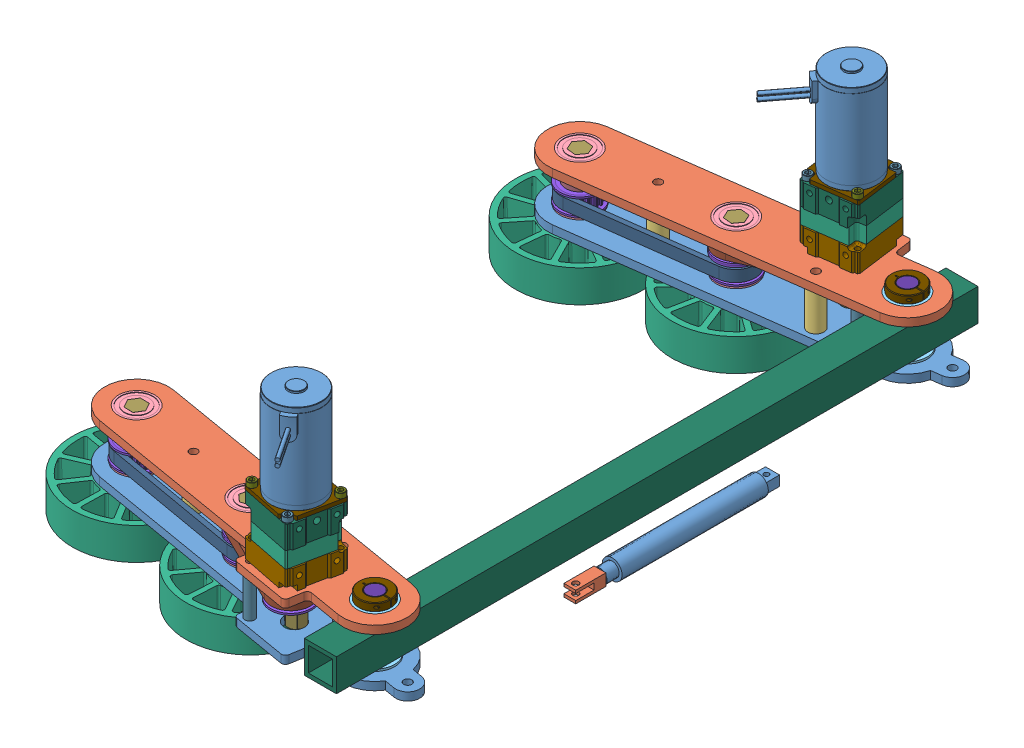
SolidWorks assembly IntakeV7Assem, configuration Default. Lengths in mm.
Overall size (329.15 194.94 529.24).
125 component instances, 38 part files, 146 mates.
Components (placement in the parent):
- IntakeV7PlateBottom-1: IntakeV7PlateBottom [Default] at (175.2787 -57.2575 -302.756) x (0.167502 0 -0.985872) z (0.985872 0 0.167502) size (67.49 6.35 297.21)
- IntakeV7PlateBottom-2: IntakeV7PlateBottom [Default] at (169.8416 -50.9075 -403.3696) x (0.134021 0 0.990979) z (0.990979 0 -0.134021) size (67.49 6.35 297.21)
- IntakeV7PlateTop-1: IntakeV7PlateTop [Default] at (175.2787 -18.6495 -302.756) x (0.167502 0 -0.985872) z (0.985872 0 0.167502) size (67.49 6.35 281.33)
- IntakeV7PlateTop-2: IntakeV7PlateTop [Default] at (169.8416 -12.2995 -403.3696) x (0.134021 0 0.990979) z (0.990979 0 -0.134021) size (67.49 6.35 281.33)
- PlateSpacer-1: PlateSpacer [Default] at (-346.0992 -18.6495 -177.4979) x (-0.995575 0 0.093974) z (0 -1 0) size (12.7 12.7 32.26)
- PlateSpacer-2: PlateSpacer [Default] at (-222.5722 -18.6495 -171.9688) x (1 0 0) z (0 -1 0) size (12.7 12.7 32.26)
- PlateSpacer-3: PlateSpacer [Default] at (-223.3522 -50.9075 -547.5543) x (1 0 0) z (0 1 0) size (12.7 12.7 32.26)
- PlateSpacer-4: PlateSpacer [Default] at (-346.9956 -50.9075 -546.2114) x (1 0 0) z (0 1 0) size (12.7 12.7 32.26)
- HalfHexBearing-1: HalfHexBearing [Default] at (-400.3258 -12.2995 -186.7111) x (0.520029 0 -0.854148) z (-0.854148 0 -0.520029) size (31.12 7.94 31.12)
- HalfHexBearing-2: HalfHexBearing [Default] at (-400.3258 -57.2575 -186.7111) x (-0.520029 0 0.854148) z (-0.854148 0 -0.520029) size (31.12 7.94 31.12)
- HalfHexBearing-3: HalfHexBearing [Default] at (-291.8726 -12.2995 -168.2847) x (-0.20332 0 0.979112) z (0.979112 0 0.20332) size (31.12 7.94 31.12)
- HalfHexBearing-4: HalfHexBearing [Default] at (-291.8726 -57.2575 -168.2847) x (0.20332 0 -0.979112) z (0.979112 0 0.20332) size (31.12 7.94 31.12)
- HalfHexBearing-5: HalfHexBearing [Default] at (-401.5031 -12.2995 -538.8398) x (-0.408462 0 -0.912775) z (-0.912775 0 0.408462) size (31.12 7.94 31.12)
- HalfHexBearing-6: HalfHexBearing [Default] at (-401.5031 -57.2575 -538.8398) x (0.408462 0 0.912775) z (-0.912775 0 0.408462) size (31.12 7.94 31.12)
- HalfHexBearing-7: HalfHexBearing [Default] at (-292.4881 -12.2995 -553.5831) x (-0.408462 0 -0.912775) z (-0.912775 0 0.408462) size (31.12 7.94 31.12)
- HalfHexBearing-8: HalfHexBearing [Default] at (-292.4881 -57.2575 -553.5831) x (0.408462 0 0.912775) z (-0.912775 0 0.408462) size (31.12 7.94 31.12)
- HalfRoundBearing-1: HalfRoundBearing [Default] at (-173.0483 -12.2995 -148.0962) x (0.837169 0 0.546944) z (0.546944 0 -0.837169) size (31.12 7.94 31.12)
- HalfRoundBearing-2: HalfRoundBearing [Default] at (-173.0483 -57.2575 -148.0962) x (-0.997571 0 -0.069658) z (0.069658 0 -0.997571) size (31.12 7.94 31.12)
- HalfRoundBearing-3: HalfRoundBearing [Default] at (-173.0483 -57.2575 -569.7362) x (-1 0 0) z (0 0 -1) size (31.12 7.94 31.12)
- HalfRoundBearing-4: HalfRoundBearing [Default] at (-173.0483 -12.2995 -569.7362) x (0.837169 0 0.546944) z (0.546944 0 -0.837169) size (31.12 7.94 31.12)
- 4inCompliantWheel-1: 4inCompliantWheel [Default] at (-284.8008 -77.497 -183.4) x (0.20332 0 -0.979112) z (0 1 0) size (101.6 101.6 25.74)
  - 4IN Compliant Wheel FINAL Overmold-1: 4IN Compliant Wheel FINAL Overmold [Default] at (-16.2374 3.8509 18.652) size (101.6 101.6 25.74)
  - 2in Wheel Intergrated 0500 HEX Hub-1: 2in Wheel Intergrated 0500 HEX Hub [Default] at (-16.2374 3.8509 5.952) x (-1 0 0) z (0 0 -1) size (41.91 41.91 25.4)
- 4inCompliantWheel-2: 4inCompliantWheel [Default] at (-416.4692 -77.497 -190.939) x (-0.999729 0 -0.023285) z (0 1 0) size (101.6 101.6 25.74)
  - 4IN Compliant Wheel FINAL Overmold-1: 4IN Compliant Wheel FINAL Overmold [Default] at (-16.2374 3.8509 18.652) size (101.6 101.6 25.74)
  - 2in Wheel Intergrated 0500 HEX Hub-1: 2in Wheel Intergrated 0500 HEX Hub [Default] at (-16.2374 3.8509 5.952) x (-1 0 0) z (0 0 -1) size (41.91 41.91 25.4)
- 4inCompliantWheel-3: 4inCompliantWheel [Default] at (-417.2595 -77.497 -544.3371) x (-0.994718 0 -0.102649) z (0 1 0) size (101.6 101.6 25.74)
  - 4IN Compliant Wheel FINAL Overmold-1: 4IN Compliant Wheel FINAL Overmold [Default] at (-16.2374 3.8509 18.652) size (101.6 101.6 25.74)
  - 2in Wheel Intergrated 0500 HEX Hub-1: 2in Wheel Intergrated 0500 HEX Hub [Default] at (-16.2374 3.8509 5.952) x (-1 0 0) z (0 0 -1) size (41.91 41.91 25.4)
- 4inCompliantWheel-4: 4inCompliantWheel [Default] at (-305.1271 -77.497 -542.6863) x (-0.586256 0 0.810126) z (0 1 0) size (101.6 101.6 25.74)
  - 4IN Compliant Wheel FINAL Overmold-1: 4IN Compliant Wheel FINAL Overmold [Default] at (-16.2374 3.8509 18.652) size (101.6 101.6 25.74)
  - 2in Wheel Intergrated 0500 HEX Hub-1: 2in Wheel Intergrated 0500 HEX Hub [Default] at (-16.2374 3.8509 5.952) x (-1 0 0) z (0 0 -1) size (41.91 41.91 25.4)
- 18THTD9MMPulley-1: 18THTD9MMPulley [Default] at (-229.0207 -27.57 -137.4686) x (0.947792 0 -0.31889) z (0 -1 0) size (32 32 14.5)
- 18THTD9MMPulley-2: 18THTD9MMPulley [Default] at (-227.7775 -27.57 -580.2764) x (1 0 0) z (0 1 0) size (32 32 14.5)
- 18THTD9MMPulley-3: 18THTD9MMPulley [Default] at (-291.8726 -42.07 -168.2847) x (0.746276 0 0.665636) z (0 -1 0) size (32 32 14.5)
- 18THTD9MMPulley-4: 18THTD9MMPulley [Default] at (-400.3258 -42.07 -186.7111) x (-0.520029 0 0.854148) z (0 1 0) size (32 32 14.5)
- 18THTD9MMPulley-5: 18THTD9MMPulley [Default] at (-401.5031 -42.07 -538.8398) x (1 0 0) z (0 1 0) size (32 32 14.5)
- 18THTD9MMPulley-6: 18THTD9MMPulley [Default] at (-292.4881 -42.07 -553.5831) x (1 0 0) z (0 1 0) size (32 32 14.5)
- 18THTD9MMPulley-7: 18THTD9MMPulley [Default] at (-291.8726 -27.57 -168.2847) x (0.20332 0 -0.979112) z (0 1 0) size (32 32 14.5)
- 18THTD9MMPulley-8: 18THTD9MMPulley [Default] at (-292.4881 -27.57 -553.5831) x (1 0 0) z (0 1 0) size (32 32 14.5)
- VersaPlanetary_v2_Single_Stage_10_1_with_BAG-1: VersaPlanetary_v2_Single_Stage_10_1_with_BAG [Default] at (-206.5577 4.3255 -136.7173) x (0 -1 0) z (0.197729 0 -0.980257) size (163.4 63.56 63.56)
  - 217-2625-026 Rev1-1: 217-2625-026 Rev1 [Default] at (-6.5 22.225 0) x (0 -1 0) z (-1 0 0) size (44.45 42 18.13)
  - 217-2742-001 Rev4-1: 217-2742-001 Rev4 [Default] at (0.2002 22.225 0) x (1 0 0) z (0 -0.092627 0.995701) size (7 28 28)
  - 217-2742-001 Rev4-2: 217-2742-001 Rev4 [Default] at (8.2002 22.225 0) size (7 28 28)
  - 217-2625-017 Rev1_9714K61-1: 217-2625-017 Rev1_9714K61 [Default] at (7.42 22.3002 -0.342) x (0 0.56703 0.823697) z (0 -0.823697 0.56703) size (28.51 4.98 30.18)
  - 217-2625-003 Rev1-1: 217-2625-003 Rev1 [Default] at (7.4478 22.225 0) x (0 -1 0) z (1 0 0) size (17 17 64.12)
  - 217-2625-018 Rev1_98541A410-1: 217-2625-018 Rev1_98541A410 [Default] at (-0.7046 22.225 0) x (1 0 0) z (0 -0.017452 0.999848) size (1 19.6 17.4)
  - 832-1750-Ring-Gear-Screw_SSA0832-0500ZC-1: 832-1750-Ring-Gear-Screw_SSA0832-0500ZC [Default] at (-30.7 4.725 -17.5) x (0 0.997447 0.071411) z (0 -0.071411 0.997447) size (6.73 48.51 6.73)
  - 832-1750-Ring-Gear-Screw_SSA0832-0500ZC-2: 832-1750-Ring-Gear-Screw_SSA0832-0500ZC [Default] at (-30.7 39.725 17.5) x (0 0.005929 0.999982) z (0 -0.999982 0.005929) size (6.73 48.51 6.73)
  - 217-2625-025 Rev1-1: 217-2625-025 Rev1 [Default] at (-23.2 22.225 0) x (0 -1 0) z (-1 0 0) size (44.45 42 18)
  - 217-4649-002 Rev1_SSA0832-0500ZC-1: 217-4649-002 Rev1_SSA0832-0500ZC [Default] at (-33.7 4.2645 17.9605) x (0 0.33842 -0.940995) z (0 0.940995 0.33842) size (6.73 16.76 6.73)
  - 217-4649-002 Rev1_SSA0832-0500ZC-2: 217-4649-002 Rev1_SSA0832-0500ZC [Default] at (-33.7 40.1855 -17.9605) x (0 -0.308932 -0.951084) z (0 0.951084 -0.308932) size (6.73 16.76 6.73)
  - 217-4649-006 Rev1_SSA0004-008BA-1: 217-4649-006 Rev1_SSA0004-008BA [Default] at (-30.7 22.225 12.5) x (0 0.5 -0.866025) z (0 -0.866025 -0.5) size (7 14 7)
  - 217-4649-006 Rev1_SSA0004-008BA-2: 217-4649-006 Rev1_SSA0004-008BA [Default] at (-30.7 22.225 -12.5) x (0 -0.5 0.866025) z (0 0.866025 0.5) size (7 14 7)
  - 217-2822-003 Rev4-1: 217-2822-003 Rev4 [Default] at (-32.2 22.225 0) x (0 -1 0) z (-1 0 0) size (42 42 4.8)
  - 217-3351 Rev2-1: 217-3351 Rev2 [Default] at (-33.7 22.225 0) x (0 0 1) z (1 0 0) size (59.11 59.11 84.5)
  - 217-2820 Rev1_Public-1: 217-2820 Rev1_Public [Default] at (-4.6546 22.225 0) x (0 -0.456494 0.889726) z (-1 0 0) size (39.26 38.9 17.4)
    - 217-2625-100-1: 217-2625-100 [Default] at origin size (39.26 38.9 12.7)
      - 217-2625-008 Rev1-1: 217-2625-008 Rev1 [Default] at origin size (34.7 34.7 4.7)
      - 217-2625-010 Rev1-1: 217-2625-010 Rev1 [Default] at (0 10.193 3.65) x (0.999813 0.019336 0) z (0 0 1) size (4 4 12)
      - 217-2625-010 Rev1-2: 217-2625-010 Rev1 [Default] at (8.691 -5.3258 3.65) size (4 4 12)
      - 217-2625-010 Rev1-3: 217-2625-010 Rev1 [Default] at (-8.691 -5.3258 3.65) size (4 4 12)
      - 217-2625-005 Rev1_Planet_Revolving_Follower01-1: 217-2625-005 Rev1_Planet_Revolving_Follower01 [Default] at (8.691 -5.3258 6.35) x (0.932816 0.360354 0) z (0 0 1) size (16.91 16.92 8)
      - 217-2625-005 Rev1_Planet_Revolving_Follower01-2: 217-2625-005 Rev1_Planet_Revolving_Follower01 [Default] at (-8.691 -5.3258 6.35) x (-0.932788 -0.360426 0) z (0 0 1) size (16.91 16.92 8)
      - 217-2625-005 Rev1_Planet_Revolving_Follower01-3: 217-2625-005 Rev1_Planet_Revolving_Follower01 [Default] at (0 10.193 6.35) x (0.893583 0.448898 0) z (0 0 1) size (16.91 16.92 8)
    - 217-2625-007 Rev1_Public-1: 217-2625-007 Rev1_Public [Default] at (0 0 6.7) x (0.992772 0.120019 0) z (0 0 1) size (14.49 14.49 12.72)
  - 217-2816-001 Rev1-1: 217-2816-001 Rev1 [Default] at (-6.35 22.225 0) x (0 -1 0) z (1 0 0) size (42 42 14.5)
  - 217-4649-001 Rev1-1: 217-4649-001 Rev1 [Default] at (-20.046 22.225 0) x (0 -1 0) z (1 0 0) size (18 18 13)
  - 217-4649-007 Rev1_94105A824-1: 217-4649-007 Rev1_94105A824 [Default] at (-25.521 22.225 -6.7835) x (-0.996104 -0.088191 0) z (0 0 -1) size (4.83 4.83 4.9)
  - 217-2625-011 Rev1-1: 217-2625-011 Rev1 [Default] at (-24.7818 22.225 0) x (0 0 1) z (0 -1 0) size (8.01 7.5 7.94)
- VersaPlanetary_v2_Single_Stage_10_1_with_BAG-2: VersaPlanetary_v2_Single_Stage_10_1_with_BAG [Default] at (-224.7989 4.3255 -558.2519) x (0 -1 0) z (0.990979 0 -0.134021) size (163.4 63.56 63.56)
  - 217-2625-026 Rev1-1: 217-2625-026 Rev1 [Default] at (-6.5 22.225 0) x (0 -1 0) z (-1 0 0) size (44.45 42 18.13)
  - 217-2742-001 Rev4-1: 217-2742-001 Rev4 [Default] at (0.2002 22.225 0) x (1 0 0) z (0 -0.092627 0.995701) size (7 28 28)
  - 217-2742-001 Rev4-2: 217-2742-001 Rev4 [Default] at (8.2002 22.225 0) size (7 28 28)
  - 217-2625-017 Rev1_9714K61-1: 217-2625-017 Rev1_9714K61 [Default] at (7.42 22.3002 -0.342) x (0 0.56703 0.823697) z (0 -0.823697 0.56703) size (28.51 4.98 30.18)
  - 217-2625-003 Rev1-1: 217-2625-003 Rev1 [Default] at (7.4478 22.225 0) x (0 -1 0) z (1 0 0) size (17 17 64.12)
  - 217-2625-018 Rev1_98541A410-1: 217-2625-018 Rev1_98541A410 [Default] at (-0.7046 22.225 0) x (1 0 0) z (0 -0.017452 0.999848) size (1 19.6 17.4)
  - 832-1750-Ring-Gear-Screw_SSA0832-0500ZC-1: 832-1750-Ring-Gear-Screw_SSA0832-0500ZC [Default] at (-30.7 4.725 -17.5) x (0 0.997447 0.071411) z (0 -0.071411 0.997447) size (6.73 48.51 6.73)
  - 832-1750-Ring-Gear-Screw_SSA0832-0500ZC-2: 832-1750-Ring-Gear-Screw_SSA0832-0500ZC [Default] at (-30.7 39.725 17.5) x (0 0.005929 0.999982) z (0 -0.999982 0.005929) size (6.73 48.51 6.73)
  - 217-2625-025 Rev1-1: 217-2625-025 Rev1 [Default] at (-23.2 22.225 0) x (0 -1 0) z (-1 0 0) size (44.45 42 18)
  - 217-4649-002 Rev1_SSA0832-0500ZC-1: 217-4649-002 Rev1_SSA0832-0500ZC [Default] at (-33.7 4.2645 17.9605) x (0 0.33842 -0.940995) z (0 0.940995 0.33842) size (6.73 16.76 6.73)
  - 217-4649-002 Rev1_SSA0832-0500ZC-2: 217-4649-002 Rev1_SSA0832-0500ZC [Default] at (-33.7 40.1855 -17.9605) x (0 -0.308932 -0.951084) z (0 0.951084 -0.308932) size (6.73 16.76 6.73)
  - 217-4649-006 Rev1_SSA0004-008BA-1: 217-4649-006 Rev1_SSA0004-008BA [Default] at (-30.7 22.225 12.5) x (0 0.5 -0.866025) z (0 -0.866025 -0.5) size (7 14 7)
  - 217-4649-006 Rev1_SSA0004-008BA-2: 217-4649-006 Rev1_SSA0004-008BA [Default] at (-30.7 22.225 -12.5) x (0 -0.5 0.866025) z (0 0.866025 0.5) size (7 14 7)
  - 217-2822-003 Rev4-1: 217-2822-003 Rev4 [Default] at (-32.2 22.225 0) x (0 -1 0) z (-1 0 0) size (42 42 4.8)
  - 217-3351 Rev2-1: 217-3351 Rev2 [Default] at (-33.7 22.225 0) x (0 0 1) z (1 0 0) size (59.11 59.11 84.5)
  - 217-2820 Rev1_Public-1: 217-2820 Rev1_Public [Default] at (-4.6546 22.225 0) x (0 -0.456494 0.889726) z (-1 0 0) size (39.26 38.9 17.4)
    - 217-2625-100-1: 217-2625-100 [Default] at origin size (39.26 38.9 12.7)
      - 217-2625-008 Rev1-1: 217-2625-008 Rev1 [Default] at origin size (34.7 34.7 4.7)
      - 217-2625-010 Rev1-1: 217-2625-010 Rev1 [Default] at (0 10.193 3.65) x (0.999813 0.019336 0) z (0 0 1) size (4 4 12)
      - 217-2625-010 Rev1-2: 217-2625-010 Rev1 [Default] at (8.691 -5.3258 3.65) size (4 4 12)
      - 217-2625-010 Rev1-3: 217-2625-010 Rev1 [Default] at (-8.691 -5.3258 3.65) size (4 4 12)
      - 217-2625-005 Rev1_Planet_Revolving_Follower01-1: 217-2625-005 Rev1_Planet_Revolving_Follower01 [Default] at (8.691 -5.3258 6.35) x (0.932816 0.360354 0) z (0 0 1) size (16.91 16.92 8)
      - 217-2625-005 Rev1_Planet_Revolving_Follower01-2: 217-2625-005 Rev1_Planet_Revolving_Follower01 [Default] at (-8.691 -5.3258 6.35) x (-0.932788 -0.360426 0) z (0 0 1) size (16.91 16.92 8)
      - 217-2625-005 Rev1_Planet_Revolving_Follower01-3: 217-2625-005 Rev1_Planet_Revolving_Follower01 [Default] at (0 10.193 6.35) x (0.893583 0.448898 0) z (0 0 1) size (16.91 16.92 8)
    - 217-2625-007 Rev1_Public-1: 217-2625-007 Rev1_Public [Default] at (0 0 6.7) x (0.992772 0.120019 0) z (0 0 1) size (14.49 14.49 12.72)
  - 217-2816-001 Rev1-1: 217-2816-001 Rev1 [Default] at (-6.35 22.225 0) x (0 -1 0) z (1 0 0) size (42 42 14.5)
  - 217-4649-001 Rev1-1: 217-4649-001 Rev1 [Default] at (-20.046 22.225 0) x (0 -1 0) z (1 0 0) size (18 18 13)
  - 217-4649-007 Rev1_94105A824-1: 217-4649-007 Rev1_94105A824 [Default] at (-25.521 22.225 -6.7835) x (-0.996104 -0.088191 0) z (0 0 -1) size (4.83 4.83 4.9)
  - 217-2625-011 Rev1-1: 217-2625-011 Rev1 [Default] at (-24.7818 22.225 0) x (0 0 1) z (0 -1 0) size (8.01 7.5 7.94)
- BetweenWheelsBelt-1: BetweenWheelsBelt [Default] at (-400.3258 -42.07 -186.7111) x (0.985049 0 0.172276) z (0 -1 0) size (140.93 30.93 9)
- BetweenWheelsBelt-2: BetweenWheelsBelt [Default] at (-401.5031 -42.07 -538.8398) x (0.991616 0 -0.129217) z (0 1 0) size (140.93 30.93 9)
- WheelToGearboxBelt-1: WheelToGearboxBelt [Default] at (-229.0207 -27.57 -137.4686) x (-0.897885 0 -0.44023) z (0 1 0) size (100.93 30.93 9)
- WheelToGearboxBelt-2: WheelToGearboxBelt [Default] at (-292.4253 -27.57 -553.0537) x (0.918758 0 -0.394822) z (0 -1 0) size (100.93 30.93 9)
- WheelAxle-1: WheelAxle [Default] at (-401.4916 -84.2577 -538.8386) x (-0.586256 0 0.810126) z (-0.810126 0 -0.586256) size (14.66 71.96 12.7)
- WheelAxle-2: WheelAxle [Default] at (-292.5043 -84.2577 -553.5948) x (0.586256 0 -0.810126) z (0.810126 0 0.586256) size (14.66 71.96 12.7)
- WheelAxle-3: WheelAxle [Default] at (-291.8531 -84.2577 -168.2806) x (0.20332 0 -0.979112) z (0.979112 0 0.20332) size (14.66 71.96 12.7)
- WheelAxle-4: WheelAxle [Default] at (-400.3429 -84.2577 -186.7215) x (0.520029 0 -0.854148) z (0.854148 0 0.520029) size (14.66 71.96 12.7)
- FrontAxleSpacer-2: FrontAxleSpacer [Default] at (-400.3258 -34.8166 -186.7111) size (22.23 14.58 22.23)
- GearboxMountSpacers-1: GearboxMountSpacers [Default] at (-207.3879 -50.9075 -154.1137) size (7.62 32.26 7.62)
- GearboxMountSpacers-2: GearboxMountSpacers [Default] at (-248.8182 -50.9075 -124.717) size (7.62 32.26 7.62)
- GearboxMountSpacers-3: GearboxMountSpacers [Default] at (-207.572 -50.9075 -564.885) size (7.62 32.26 7.62)
- GearboxMountSpacers-4: GearboxMountSpacers [Default] at (-247.9831 -50.9075 -595.6678) size (7.62 32.26 7.62)
- ArmMountBar-1: ArmMountBar [Default] at (-173.0483 -36.62 -612.9162) size (50.8 25.4 508)
- PivotSpacer-1: PivotSpacer [Default] at (-173.0483 -20.237 -148.0962) x (1 0 0) z (0 -1 0) size (19.05 19.05 3.68)
- PivotSpacer-2: PivotSpacer [Default] at (-173.0483 -20.237 -569.7362) x (1 0 0) z (0 -1 0) size (19.05 19.05 3.68)
- FrontAxleSpacer-1: FrontAxleSpacer [Default] at (-401.5031 -34.8166 -538.8398) size (22.23 14.58 22.23)
- ArmPivotAxle-1: ArmPivotAxle [Default] at (-173.0483 -63.6075 -148.0962) size (12.7 57.66 12.7)
- ArmPivotAxle-2: ArmPivotAxle [Default] at (-173.0483 -63.6075 -569.7362) size (12.7 57.66 12.7)
- HalfRoundShaftCollar-1: HalfRoundShaftCollar [Default] at (-168.5329 -8.5224 -150.7118) x (1 0 0) z (0 -1 0) size (25.39 25.4 6.35)
- HalfRoundShaftCollar-2: HalfRoundShaftCollar [Default] at (-169.5026 -59.8304 -151.9248) x (0.955715 0 -0.294293) z (0 -1 0) size (25.39 25.4 6.35)
- HalfRoundShaftCollar-3: HalfRoundShaftCollar [Default] at (-168.5329 -8.5224 -572.3518) x (1 0 0) z (0 -1 0) size (25.39 25.4 6.35)
- HalfRoundShaftCollar-4: HalfRoundShaftCollar [Default] at (-169.3234 -59.8304 -573.3906) x (0.968711 0 -0.248193) z (0 -1 0) size (25.39 25.4 6.35)
- CylinderBody-1: CylinderBody [Default] at (-149.2993 -61.9565 -428.0042) x (0 -1 0) z (0 0 1) size (15.75 15.75 136.65)
- PistonRod-1: PistonRod [Default] at (-149.2993 -61.9565 -302.5282) size (9.4 9.4 125.48)
Mates (geometry in assembly coordinates):
- Concentric1: concentric aligned: cylinder of IntakeV7PlateBottom-1 through (-400.3258 -50.9075 -186.7111) axis (0 -1 0) radius 14.2748; cylinder of IntakeV7PlateTop-1 through (-400.3258 -12.2995 -186.7111) axis (0 -1 0) radius 14.2748
- Concentric2: concentric aligned: cylinder of IntakeV7PlateBottom-1 through (-173.0483 -50.9075 -148.0962) axis (0 -1 0) radius 14.2748; cylinder of IntakeV7PlateTop-1 through (-173.0483 -12.2995 -148.0962) axis (0 -1 0) radius 14.2748
- Distance1: distance = 32.258 mm anti-aligned: plane of IntakeV7PlateTop-1 through (175.2787 -18.6495 -302.756) normal (0 -1 0); plane of IntakeV7PlateBottom-1 through (175.2787 -50.9075 -302.756) normal (0 1 0)
- Coincident2: coincident aligned: plane of IntakeV7PlateBottom-1 through (175.2787 -57.2575 -302.756) normal (0 -1 0); plane of IntakeV7PlateBottom-2 through (169.8416 -57.2575 -403.3696) normal (0 -1 0)
- Concentric3: concentric aligned: cylinder of IntakeV7PlateBottom-2 through (-173.0483 -57.2575 -569.7362) axis (0 1 0) radius 14.2748; cylinder of IntakeV7PlateTop-2 through (-173.0483 -18.6495 -569.7362) axis (0 1 0) radius 14.2748
- Concentric4: concentric aligned: cylinder of IntakeV7PlateBottom-2 through (-401.5031 -57.2575 -538.8398) axis (0 1 0) radius 14.2748; cylinder of IntakeV7PlateTop-2 through (-401.5031 -18.6495 -538.8398) axis (0 1 0) radius 14.2748
- Coincident3: coincident aligned: plane of IntakeV7PlateTop-1 through (175.2787 -12.2995 -302.756) normal (0 1 0); plane of IntakeV7PlateTop-2 through (169.8416 -12.2995 -403.3696) normal (0 1 0)
- Coincident4: coincident anti-aligned: plane of IntakeV7PlateTop-1 through (175.2787 -18.6495 -302.756) normal (0 -1 0); plane of PlateSpacer-1 through (-346.0992 -18.6495 -177.4979) normal (0 1 0)
- Coincident5: coincident anti-aligned: plane of IntakeV7PlateTop-1 through (175.2787 -18.6495 -302.756) normal (0 -1 0); plane of PlateSpacer-2 through (-222.5722 -18.6495 -171.9688) normal (0 1 0)
- Coincident6: coincident anti-aligned: plane of IntakeV7PlateTop-2 through (169.8416 -18.6495 -403.3696) normal (0 -1 0); plane of PlateSpacer-4 through (-346.9956 -18.6495 -546.2114) normal (0 1 0)
- Coincident7: coincident anti-aligned: plane of IntakeV7PlateBottom-2 through (169.8416 -50.9075 -403.3696) normal (0 1 0); plane of PlateSpacer-3 through (-223.3522 -50.9075 -547.5543) normal (0 -1 0)
- Concentric9: concentric anti-aligned: cylinder of IntakeV7PlateTop-2 through (-401.5031 -18.6495 -538.8398) axis (0 1 0) radius 14.2748; cylinder of HalfHexBearing-5 through (-401.5031 -12.2995 -538.8398) axis (0 -1 0) radius 14.2748
- Coincident8: coincident anti-aligned: plane of IntakeV7PlateTop-2 through (169.8416 -18.6495 -403.3696) normal (0 -1 0); plane of HalfHexBearing-5 through (-407.8578 -18.6495 -553.0403) normal (0 1 0)
- Concentric10: concentric aligned: cylinder of IntakeV7PlateBottom-2 through (-401.5031 -57.2575 -538.8398) axis (0 1 0) radius 14.2748; cylinder of HalfHexBearing-6 through (-401.5031 -57.2575 -538.8398) axis (0 1 0) radius 14.2748
- Coincident9: coincident anti-aligned: plane of IntakeV7PlateBottom-2 through (169.8416 -50.9075 -403.3696) normal (0 1 0); plane of HalfHexBearing-6 through (-395.1485 -50.9075 -524.6393) normal (0 -1 0)
- Concentric11: concentric aligned: cylinder of IntakeV7PlateTop-1 through (-400.3258 -12.2995 -186.7111) axis (0 -1 0) radius 14.2748; cylinder of HalfHexBearing-1 through (-400.3258 -12.2995 -186.7111) axis (0 -1 0) radius 14.2748
- Concentric12: concentric anti-aligned: cylinder of IntakeV7PlateBottom-1 through (-400.3258 -50.9075 -186.7111) axis (0 -1 0) radius 14.2748; cylinder of HalfHexBearing-2 through (-400.3258 -57.2575 -186.7111) axis (0 1 0) radius 14.2748
- Coincident11: coincident anti-aligned: plane of IntakeV7PlateBottom-1 through (175.2787 -50.9075 -302.756) normal (0 1 0); plane of HalfHexBearing-2 through (-408.4162 -50.9075 -173.4227) normal (0 -1 0)
- Concentric13: concentric aligned: cylinder of IntakeV7PlateTop-1 through (-291.8726 -12.2995 -168.2847) axis (0 -1 0) radius 14.2748; cylinder of HalfHexBearing-3 through (-291.8726 -12.2995 -168.2847) axis (0 -1 0) radius 14.2748
- Coincident12: coincident anti-aligned: plane of IntakeV7PlateTop-1 through (175.2787 -18.6495 -302.756) normal (0 -1 0); plane of HalfHexBearing-3 through (-295.0358 -18.6495 -153.0521) normal (0 1 0)
- Concentric14: concentric anti-aligned: cylinder of IntakeV7PlateBottom-1 through (-291.8726 -50.9075 -168.2847) axis (0 -1 0) radius 14.2748; cylinder of HalfHexBearing-4 through (-291.8726 -57.2575 -168.2847) axis (0 1 0) radius 14.2748
- Coincident13: coincident anti-aligned: plane of IntakeV7PlateBottom-1 through (175.2787 -50.9075 -302.756) normal (0 1 0); plane of HalfHexBearing-4 through (-288.7095 -50.9075 -183.5172) normal (0 -1 0)
- Concentric15: concentric anti-aligned: cylinder of IntakeV7PlateTop-2 through (-292.4881 -18.6495 -553.5831) axis (0 1 0) radius 14.2748; cylinder of HalfHexBearing-7 through (-292.4881 -12.2995 -553.5831) axis (0 -1 0) radius 14.2748
- Coincident14: coincident anti-aligned: plane of IntakeV7PlateTop-2 through (169.8416 -18.6495 -403.3696) normal (0 -1 0); plane of HalfHexBearing-7 through (-298.8428 -18.6495 -567.7836) normal (0 1 0)
- Concentric16: concentric aligned: cylinder of IntakeV7PlateBottom-2 through (-292.4881 -57.2575 -553.5831) axis (0 1 0) radius 14.2748; cylinder of HalfHexBearing-8 through (-292.4881 -57.2575 -553.5831) axis (0 1 0) radius 14.2748
- Coincident15: coincident anti-aligned: plane of IntakeV7PlateBottom-2 through (169.8416 -50.9075 -403.3696) normal (0 1 0); plane of HalfHexBearing-8 through (-286.1335 -50.9075 -539.3826) normal (0 -1 0)
- Coincident16: coincident aligned: plane of HalfHexBearing-7 through (-295.4878 -12.2995 -560.2864) normal (-0.102649 0 0.994718); plane of HalfHexBearing-8 through (-288.1827 -57.2575 -559.5326) normal (-0.102649 0 0.994718)
- Coincident17: coincident aligned: plane of HalfHexBearing-5 through (-404.5028 -12.2995 -545.5431) normal (-0.102649 0 0.994718); plane of HalfHexBearing-6 through (-397.1977 -57.2575 -544.7893) normal (-0.102649 0 0.994718)
- Coincident18: coincident aligned: plane of HalfHexBearing-1 through (-396.5068 -12.2995 -192.9839) normal (-0.877433 0 0.479699); plane of HalfHexBearing-2 through (-392.9839 -57.2575 -186.5401) normal (-0.877433 0 0.479699)
- Coincident19: coincident aligned: plane of HalfHexBearing-3 through (-293.3658 -12.2995 -161.0942) normal (0.665636 0 -0.746276); plane of HalfHexBearing-4 through (-298.8464 -57.2575 -165.9825) normal (0.665636 0 -0.746276)
- Concentric17: concentric aligned: cylinder of IntakeV7PlateTop-1 through (-173.0483 -12.2995 -148.0962) axis (0 -1 0) radius 14.2748; cylinder of HalfRoundBearing-1 through (-173.0483 -12.2995 -148.0962) axis (0 -1 0) radius 14.2875
- Coincident20: coincident anti-aligned: plane of IntakeV7PlateTop-1 through (175.2787 -18.6495 -302.756) normal (0 -1 0); plane of HalfRoundBearing-1 through (-160.024 -18.6495 -139.5871) normal (0 1 0)
- Concentric18: concentric anti-aligned: cylinder of IntakeV7PlateBottom-1 through (-173.0483 -50.9075 -148.0962) axis (0 -1 0) radius 14.2748; cylinder of HalfRoundBearing-2 through (-173.0483 -57.2575 -148.0962) axis (0 1 0) radius 14.2875
- Concentric19: concentric anti-aligned: cylinder of IntakeV7PlateTop-2 through (-173.0483 -18.6495 -569.7362) axis (0 1 0) radius 14.2748; cylinder of HalfRoundBearing-4 through (-173.0483 -12.2995 -569.7362) axis (0 -1 0) radius 14.2875
- Coincident22: coincident anti-aligned: plane of IntakeV7PlateTop-2 through (169.8416 -18.6495 -403.3696) normal (0 -1 0); plane of HalfRoundBearing-4 through (-160.024 -18.6495 -561.2271) normal (0 1 0)
- Concentric20: concentric aligned: cylinder of IntakeV7PlateBottom-2 through (-173.0483 -57.2575 -569.7362) axis (0 1 0) radius 14.2748; cylinder of HalfRoundBearing-3 through (-173.0483 -57.2575 -569.7362) axis (0 1 0) radius 14.2875
- Coincident23: coincident anti-aligned: plane of IntakeV7PlateBottom-2 through (169.8416 -50.9075 -403.3696) normal (0 1 0); plane of HalfRoundBearing-3 through (-188.6058 -50.9075 -569.7362) normal (0 -1 0)
- Concentric21: concentric aligned: cylinder of HalfHexBearing-3 through (-291.8726 -12.2995 -168.2847) axis (0 -1 0) radius 15.5575; cylinder of 4inCompliantWheel-1/4IN Compliant Wheel FINAL Overmold-1 through (-291.8726 -29.0488 -168.2847) axis (0 -1 0) radius 50.8
- Parallel1: parallel aligned: plane of HalfHexBearing-4 through (-297.3532 -57.2575 -173.173) normal (0.979112 0 0.20332); plane of 4inCompliantWheel-1/2in Wheel Intergrated 0500 HEX Hub-1 through (-297.3665 -84.245 -173.1849) normal (0.979112 0 0.20332)
- Coincident26: coincident anti-aligned: plane of IntakeV7PlateBottom-1 through (175.2787 -50.9075 -302.756) normal (0 1 0); plane of HalfRoundBearing-2 through (-188.568 -50.9075 -149.1799) normal (0 -1 0)
- Distance3: distance = 1.5875 mm anti-aligned: plane of 4inCompliantWheel-1/2in Wheel Intergrated 0500 HEX Hub-1 through (-294.3596 -58.845 -168.8011) normal (0 1 0); plane of IntakeV7PlateBottom-1 through (175.2787 -57.2575 -302.756) normal (0 -1 0)
- Concentric22: concentric aligned: cylinder of HalfHexBearing-1 through (-400.3258 -12.2995 -186.7111) axis (0 -1 0) radius 15.5575; cone of 4inCompliantWheel-2/2in Wheel Intergrated 0500 HEX Hub-1 through (-400.3258 -59.3713 -186.7111) axis (0 -1 0)
- Coincident28: coincident aligned: plane of 4inCompliantWheel-1/4IN Compliant Wheel FINAL Overmold-1 through (-317.3029 -84.245 -173.5655) normal (0 -1 0); plane of 4inCompliantWheel-2/4IN Compliant Wheel FINAL Overmold-1 through (-400.9306 -84.245 -160.7453) normal (0 -1 0)
- Concentric23: concentric aligned: cylinder of HalfHexBearing-5 through (-401.5031 -12.2995 -538.8398) axis (0 -1 0) radius 15.5575; cone of 4inCompliantWheel-3/2in Wheel Intergrated 0500 HEX Hub-1 through (-401.5031 -59.3713 -538.8398) axis (0 -1 0)
- Coincident29: coincident aligned: plane of 4inCompliantWheel-1/4IN Compliant Wheel FINAL Overmold-1 through (-317.3029 -84.245 -173.5655) normal (0 -1 0); plane of 4inCompliantWheel-3/4IN Compliant Wheel FINAL Overmold-1 through (-404.1692 -84.245 -513.0042) normal (0 -1 0)
- Concentric24: concentric aligned: cylinder of HalfHexBearing-7 through (-292.4881 -12.2995 -553.5831) axis (0 -1 0) radius 15.5575; cone of 4inCompliantWheel-4/2in Wheel Intergrated 0500 HEX Hub-1 through (-292.4881 -59.3713 -553.5831) axis (0 -1 0)
- Coincident30: coincident aligned: plane of 4inCompliantWheel-3/4IN Compliant Wheel FINAL Overmold-1 through (-404.1692 -84.245 -513.0042) normal (0 -1 0); plane of 4inCompliantWheel-4/4IN Compliant Wheel FINAL Overmold-1 through (-271.4469 -84.245 -538.3564) normal (0 -1 0)
- Parallel2: parallel aligned: plane of HalfHexBearing-8 through (-288.1827 -57.2575 -559.5326) normal (-0.102649 0 0.994718); plane of 4inCompliantWheel-4/2in Wheel Intergrated 0500 HEX Hub-1 through (-288.1723 -84.245 -559.547) normal (-0.102649 0 0.994718)
- Parallel3: parallel aligned: plane of HalfHexBearing-6 through (-397.1977 -57.2575 -544.7893) normal (-0.102649 0 0.994718); plane of 4inCompliantWheel-3/2in Wheel Intergrated 0500 HEX Hub-1 through (-397.1873 -84.245 -544.8037) normal (-0.102649 0 0.994718)
- Parallel4: parallel aligned: plane of HalfHexBearing-2 through (-392.9839 -57.2575 -186.5401) normal (-0.877433 0 0.479699); plane of 4inCompliantWheel-2/2in Wheel Intergrated 0500 HEX Hub-1 through (-392.9661 -84.245 -186.5397) normal (-0.877433 0 0.479699)
- Concentric25: concentric anti-aligned: cylinder of HalfHexBearing-1 through (-400.3258 -12.2995 -186.7111) axis (0 -1 0) radius 15.5575; cylinder of 18THTD9MMPulley-4 through (-400.3258 -42.07 -186.7111) axis (0 1 0) radius 16
- Parallel5: parallel: plane of HalfHexBearing-2 through (-402.5542 -57.2575 -200.1233) normal (0.854148 0 0.520029); plane of 18THTD9MMPulley-4 through (-404.4552 -34.82 -196.9818) normal (0.854148 0 0.520029)
- Concentric26: concentric aligned: cylinder of HalfHexBearing-4 through (-291.8726 -57.2575 -168.2847) axis (0 1 0) radius 15.5575; cylinder of 18THTD9MMPulley-3 through (-291.8726 -42.07 -168.2847) axis (0 1 0) radius 16
- Parallel6: parallel: plane of HalfHexBearing-4 through (-292.689 -57.2575 -164.7374) normal (-0.313476 0 -0.949596); plane of 18THTD9MMPulley-3 through (-289.2053 -49.32 -165.898) normal (-0.313476 0 -0.949596)
- Concentric27: concentric aligned: cylinder of HalfHexBearing-3 through (-291.8726 -12.2995 -168.2847) axis (0 -1 0) radius 15.5575; cylinder of 18THTD9MMPulley-7 through (-291.8726 -27.57 -168.2847) axis (0 -1 0) radius 16
- Parallel7: parallel: plane of HalfHexBearing-3 through (-298.1696 -12.2995 -169.6258) normal (0.979112 0 0.20332); plane of 18THTD9MMPulley-7 through (-297.4132 -20.32 -173.219) normal (0.979112 0 0.20332)
- Coincident37: coincident anti-aligned: circle of 18THTD9MMPulley-3; circle of 18THTD9MMPulley-7
- Coincident38: coincident anti-aligned: plane of HalfHexBearing-4 through (-290.5816 -49.32 -174.502) normal (0 1 0); plane of 18THTD9MMPulley-3 through (-291.8726 -49.32 -168.2847) normal (0 -1 0)
- Concentric30: concentric anti-aligned: cylinder of HalfHexBearing-6 through (-401.5031 -57.2575 -538.8398) axis (0 1 0) radius 15.5575; cylinder of 18THTD9MMPulley-5 through (-401.5031 -42.07 -538.8398) axis (0 -1 0) radius 16
- Coincident39: coincident anti-aligned: plane of HalfHexBearing-6 through (-398.9094 -49.32 -533.0437) normal (0 1 0); plane of 18THTD9MMPulley-5 through (-401.5031 -49.32 -538.8398) normal (0 -1 0)
- Coincident41: coincident anti-aligned: plane of HalfHexBearing-8 through (-289.8944 -49.32 -547.7869) normal (0 1 0); plane of 18THTD9MMPulley-6 through (-292.4881 -49.32 -553.5831) normal (0 -1 0)
- Concentric31: concentric aligned: cylinder of HalfHexBearing-8 through (-292.4881 -57.2575 -553.5831) axis (0 1 0) radius 15.5575; cylinder of 18THTD9MMPulley-6 through (-292.4881 -42.07 -553.5831) axis (0 1 0) radius 16
- Coincident42: coincident anti-aligned: circle of 18THTD9MMPulley-6; circle of 18THTD9MMPulley-8
- Coincident43: coincident: plane of IntakeV7PlateTop-1 through (179.8685 -12.2995 -291.9749) normal (0 1 0); plane of VersaPlanetary_v2_Single_Stage_10_1_with_BAG-1/217-2625-026 Rev1-1 through (-245.7356 -12.2995 -167.2926) normal (0 -1 0)
- Concentric32: concentric: cylinder of IntakeV7PlateTop-1 through (-207.1867 -12.2995 -155.1664) axis (0 -1 0) radius 2.4892; cylinder of VersaPlanetary_v2_Single_Stage_10_1_with_BAG-1/217-2625-026 Rev1-1 through (-207.1867 4.3255 -155.1664) axis (0 1 0) radius 2.0193
- Concentric33: concentric: cylinder of IntakeV7PlateTop-1 through (-249.5011 -12.2995 -127.0572) axis (0 -1 0) radius 2.4892; cylinder of VersaPlanetary_v2_Single_Stage_10_1_with_BAG-1/217-2625-026 Rev1-1 through (-249.5011 4.3255 -127.0572) axis (0 1 0) radius 2.0193
- Concentric34: concentric: cylinder of 18THTD9MMPulley-1 through (-228.3439 -27.57 -141.1118) axis (0 1 0) radius 16; cylinder of VersaPlanetary_v2_Single_Stage_10_1_with_BAG-1/217-2625-003 Rev1-1 through (-228.3439 -52.8747 -141.1118) axis (0 -1 0) radius 2.5527
- Coincident46: coincident: plane of 18THTD9MMPulley-1 through (-230.3688 -34.82 -147.1303) normal (0.31889 0 0.947792); plane of VersaPlanetary_v2_Single_Stage_10_1_with_BAG-1/217-2625-003 Rev1-1 through (-233.8436 -52.8747 -145.9612) normal (-0.31889 0 -0.947792)
- Coincident47: coincident anti-aligned: plane of 18THTD9MMPulley-1 through (-229.0207 -20.32 -137.4686) normal (0 1 0); circle of 18THTD9MMPulley-7
- Coincident48: coincident anti-aligned: plane of IntakeV7PlateTop-1 through (175.2787 -18.6495 -302.756) normal (0 -1 0); plane of HalfHexBearing-1 through (-392.2355 -18.6495 -199.9995) normal (0 1 0)
- Concentric35: concentric: cylinder of IntakeV7PlateTop-2 through (-227.7775 -18.6495 -580.2764) axis (0 1 0) radius 9.525; cylinder of VersaPlanetary_v2_Single_Stage_10_1_with_BAG-2/217-2625-003 Rev1-1 through (-227.7775 -52.8747 -580.2764) axis (0 -1 0) radius 2.5527
- Concentric36: concentric: cylinder of IntakeV7PlateTop-2 through (-207.572 -18.6495 -564.885) axis (0 1 0) radius 2.4892; cylinder of VersaPlanetary_v2_Single_Stage_10_1_with_BAG-2/217-2625-026 Rev1-1 through (-207.572 4.3255 -564.885) axis (0 1 0) radius 2.0193
- Coincident49: coincident: plane of IntakeV7PlateTop-2 through (169.8416 -12.2995 -403.3696) normal (0 1 0); plane of VersaPlanetary_v2_Single_Stage_10_1_with_BAG-2/217-2625-026 Rev1-1 through (-208.7316 -12.2995 -605.2795) normal (0 -1 0)
- Concentric37: concentric anti-aligned: cylinder of IntakeV7PlateBottom-2 through (-227.7775 -57.2575 -580.2764) axis (0 1 0) radius 7.9375; cylinder of 18THTD9MMPulley-2 through (-227.7775 -27.57 -580.2764) axis (0 -1 0) radius 16
- Coincident51: coincident aligned: plane of 18THTD9MMPulley-2 through (-227.7775 -20.32 -580.2764) normal (0 1 0); plane of 18THTD9MMPulley-8 through (-292.4881 -20.32 -553.5831) normal (0 1 0)
- Concentric38: concentric anti-aligned: cylinder of IntakeV7PlateTop-1 through (-400.3258 -12.2995 -186.7111) axis (0 -1 0) radius 25.4; cylinder of BetweenWheelsBelt-1 through (-400.3258 -46.57 -186.7111) axis (0 1 0) radius 11.657
- Width1: width anti-aligned: plane of 18THTD9MMPulley-4 through (-400.3258 -47.57 -186.7111) normal (0 1 0); plane of 18THTD9MMPulley-4 through (-400.3258 -36.57 -186.7111) normal (0 -1 0); plane of BetweenWheelsBelt-1 through (-400.3258 -46.57 -186.7111) normal (0 -1 0); plane of BetweenWheelsBelt-1 through (-400.3258 -37.57 -186.7111) normal (0 1 0)
- Coincident53: coincident anti-aligned: plane of HalfHexBearing-2 through (-403.628 -49.32 -181.2872) normal (0 1 0); plane of 18THTD9MMPulley-4 through (-400.3258 -49.32 -186.7111) normal (0 -1 0)
- Parallel8: parallel anti-aligned: cylinder of 18THTD9MMPulley-3 through (-291.8726 -42.07 -168.2847) axis (0 -1 0) radius 16; cylinder of BetweenWheelsBelt-1 through (-291.9705 -46.57 -167.7607) axis (0 1 0) radius 15.467
- Concentric40: concentric anti-aligned: cylinder of IntakeV7PlateBottom-2 through (-401.5031 -57.2575 -538.8398) axis (0 1 0) radius 25.4; cylinder of BetweenWheelsBelt-2 through (-401.5031 -37.57 -538.8398) axis (0 -1 0) radius 11.657
- Width2: width aligned: plane of BetweenWheelsBelt-2 through (-401.5031 -37.57 -538.8398) normal (0 1 0); plane of BetweenWheelsBelt-2 through (-401.5031 -46.57 -538.8398) normal (0 -1 0); plane of 18THTD9MMPulley-5 through (-401.5031 -47.57 -538.8398) normal (0 1 0); plane of 18THTD9MMPulley-5 through (-401.5031 -36.57 -538.8398) normal (0 -1 0)
- Tangent1: tangent aligned: cylinder of 18THTD9MMPulley-6 through (-292.4881 -42.07 -553.5831) axis (0 1 0) radius 16; cylinder of BetweenWheelsBelt-2 through (-292.4253 -37.57 -553.0537) axis (0 -1 0) radius 15.467
- Concentric43: concentric anti-aligned: cylinder of BetweenWheelsBelt-2 through (-292.4253 -37.57 -553.0537) axis (0 -1 0) radius 15.467; cylinder of WheelToGearboxBelt-2 through (-292.4253 -32.07 -553.0537) axis (0 1 0) radius 15.467
- Width3: width anti-aligned: plane of WheelToGearboxBelt-2 through (-292.4253 -32.07 -553.0537) normal (0 -1 0); plane of WheelToGearboxBelt-2 through (-292.4253 -23.07 -553.0537) normal (0 1 0); plane of 18THTD9MMPulley-8 through (-292.4881 -33.07 -553.5831) normal (0 1 0); plane of 18THTD9MMPulley-8 through (-292.4881 -22.07 -553.5831) normal (0 -1 0)
- Tangent3: tangent aligned: cylinder of 18THTD9MMPulley-2 through (-227.7775 -27.57 -580.2764) axis (0 -1 0) radius 16; cylinder of WheelToGearboxBelt-2 through (-228.1123 -32.07 -580.6913) axis (0 1 0) radius 15.467
- Concentric46: concentric anti-aligned: cylinder of 18THTD9MMPulley-7 through (-291.8726 -27.57 -168.2847) axis (0 1 0) radius 16; cylinder of WheelToGearboxBelt-1 through (-291.8726 -23.07 -168.2847) axis (0 -1 0) radius 11.657
- Concentric47: concentric anti-aligned: cylinder of 18THTD9MMPulley-1 through (-229.0207 -27.57 -137.4686) axis (0 1 0) radius 16; cylinder of WheelToGearboxBelt-1 through (-229.0207 -23.07 -137.4686) axis (0 -1 0) radius 15.467
- Width4: width anti-aligned: plane of WheelToGearboxBelt-1 through (-229.0207 -23.07 -137.4686) normal (0 1 0); plane of WheelToGearboxBelt-1 through (-229.0207 -32.07 -137.4686) normal (0 -1 0); plane of 18THTD9MMPulley-1 through (-229.0207 -22.07 -137.4686) normal (0 -1 0); plane of 18THTD9MMPulley-1 through (-229.0207 -33.07 -137.4686) normal (0 1 0)
- Coincident55: coincident anti-aligned: plane of HalfHexBearing-5 through (-394.198 -12.2995 -538.086) normal (-0.810126 0 -0.586256); plane of WheelAxle-1 through (-398.4966 -12.2995 -532.1458) normal (0.810126 0 0.586256)
- Coincident56: coincident anti-aligned: plane of HalfHexBearing-5 through (-397.1977 -12.2995 -544.7893) normal (-0.912775 0 0.408462); plane of WheelAxle-1 through (-394.198 -12.2995 -538.086) normal (0.912775 0 -0.408462)
- Coincident57: coincident aligned: plane of HalfHexBearing-5 through (-405.4456 -12.2995 -547.6499) normal (0 1 0); plane of WheelAxle-1 through (-401.4916 -12.2995 -538.8386) normal (0 1 0)
- Coincident58: coincident anti-aligned: plane of HalfHexBearing-7 through (-296.7935 -12.2995 -547.6336) normal (0.912775 0 -0.408462); plane of WheelAxle-2 through (-299.798 -12.2995 -554.3475) normal (-0.912775 0 0.408462)
- Coincident59: coincident anti-aligned: plane of HalfHexBearing-7 through (-295.4878 -12.2995 -560.2864) normal (-0.102649 0 0.994718); plane of WheelAxle-2 through (-288.2057 -12.2995 -559.5349) normal (0.102649 0 -0.994718)
- Coincident60: coincident aligned: plane of HalfHexBearing-7 through (-296.4306 -12.2995 -562.3932) normal (0 1 0); plane of WheelAxle-2 through (-292.5043 -12.2995 -553.5948) normal (0 1 0)
- Coincident61: coincident anti-aligned: plane of HalfHexBearing-1 through (-404.1449 -12.2995 -180.4383) normal (0.877433 0 -0.479699); plane of WheelAxle-4 through (-407.6733 -12.2995 -186.8922) normal (-0.877433 0 0.479699)
- Coincident62: coincident anti-aligned: plane of HalfHexBearing-1 through (-403.8487 -12.2995 -193.1549) normal (-0.023285 0 0.999729); plane of WheelAxle-4 through (-396.5299 -12.2995 -192.9844) normal (0.023285 0 -0.999729)
- Coincident63: coincident aligned: plane of HalfHexBearing-1 through (-395.3065 -12.2995 -194.9553) normal (0 1 0); plane of WheelAxle-4 through (-400.3429 -12.2995 -186.7215) normal (0 1 0)
- Coincident64: coincident anti-aligned: plane of HalfHexBearing-3 through (-286.3921 -12.2995 -163.3963) normal (-0.313476 0 -0.949596); plane of WheelAxle-3 through (-293.3439 -12.2995 -161.1014) normal (0.313476 0 0.949596)
- Coincident66: coincident anti-aligned: plane of HalfHexBearing-3 through (-290.3795 -12.2995 -175.4752) normal (-0.665636 0 0.746276); plane of WheelAxle-3 through (-284.8903 -12.2995 -170.5791) normal (0.665636 0 -0.746276)
- Coincident67: coincident aligned: plane of HalfHexBearing-3 through (-293.8351 -12.2995 -158.8343) normal (0 1 0); plane of WheelAxle-3 through (-291.8531 -12.2995 -168.2806) normal (0 1 0)
- Coincident68: coincident anti-aligned: plane of HalfHexBearing-5 through (-404.0968 -20.237 -544.6359) normal (0 -1 0); plane of FrontAxleSpacer-1 through (-401.5031 -20.237 -538.8398) normal (0 1 0)
- Concentric49: concentric aligned: cylinder of 18THTD9MMPulley-5 through (-401.5031 -42.07 -538.8398) axis (0 -1 0) radius 16; cylinder of FrontAxleSpacer-1 through (-401.5031 -20.237 -538.8398) axis (0 -1 0) radius 11.1125
- Coincident69: coincident anti-aligned: plane of HalfHexBearing-1 through (-397.0236 -20.237 -192.1349) normal (0 -1 0); plane of FrontAxleSpacer-2 through (-400.3258 -20.237 -186.7111) normal (0 1 0)
- Concentric50: concentric aligned: cylinder of 18THTD9MMPulley-4 through (-400.3258 -42.07 -186.7111) axis (0 -1 0) radius 16; cylinder of FrontAxleSpacer-2 through (-400.3258 -20.237 -186.7111) axis (0 -1 0) radius 11.1125
- Concentric51: concentric anti-aligned: cylinder of IntakeV7PlateBottom-1 through (-222.5722 -50.9075 -171.9688) axis (0 -1 0) radius 3.175; cylinder of PlateSpacer-2 through (-222.5722 -50.9075 -171.9688) axis (0 1 0) radius 3.175
- Concentric53: concentric anti-aligned: cylinder of IntakeV7PlateBottom-1 through (-346.0992 -50.9075 -177.4979) axis (0 -1 0) radius 3.175; cylinder of PlateSpacer-1 through (-346.0992 -50.9075 -177.4979) axis (0 1 0) radius 3.175
- Concentric54: concentric anti-aligned: cylinder of IntakeV7PlateBottom-2 through (-223.3522 -57.2575 -547.5543) axis (0 1 0) radius 3.175; cylinder of PlateSpacer-3 through (-223.3522 -18.6495 -547.5543) axis (0 -1 0) radius 3.175
- Concentric55: concentric anti-aligned: cylinder of IntakeV7PlateTop-2 through (-346.9956 -18.6495 -546.2114) axis (0 1 0) radius 3.175; cylinder of PlateSpacer-4 through (-346.9956 -18.6495 -546.2114) axis (0 -1 0) radius 3.175
- Concentric56: concentric aligned: cylinder of IntakeV7PlateBottom-1 through (-248.8182 -50.9075 -124.717) axis (0 -1 0) radius 2.4892; cylinder of GearboxMountSpacers-2 through (-248.8182 -18.6495 -124.717) axis (0 -1 0) radius 2.4892
- Coincident70: coincident anti-aligned: plane of IntakeV7PlateTop-1 through (175.2787 -18.6495 -302.756) normal (0 -1 0); plane of GearboxMountSpacers-2 through (-248.8182 -18.6495 -124.717) normal (0 1 0)
- Concentric57: concentric aligned: cylinder of IntakeV7PlateBottom-1 through (-207.3879 -50.9075 -154.1137) axis (0 -1 0) radius 2.4892; cylinder of GearboxMountSpacers-1 through (-207.3879 -18.6495 -154.1137) axis (0 -1 0) radius 2.4892
- Coincident71: coincident anti-aligned: plane of IntakeV7PlateBottom-1 through (175.2787 -50.9075 -302.756) normal (0 1 0); plane of GearboxMountSpacers-1 through (-207.3879 -50.9075 -154.1137) normal (0 -1 0)
- Concentric58: concentric anti-aligned: cylinder of IntakeV7PlateBottom-2 through (-207.572 -57.2575 -564.885) axis (0 1 0) radius 2.4892; cylinder of GearboxMountSpacers-3 through (-207.572 -18.6495 -564.885) axis (0 -1 0) radius 2.4892
- Coincident72: coincident anti-aligned: plane of IntakeV7PlateTop-2 through (169.8416 -18.6495 -403.3696) normal (0 -1 0); plane of GearboxMountSpacers-3 through (-207.572 -18.6495 -564.885) normal (0 1 0)
- Concentric59: concentric anti-aligned: cylinder of IntakeV7PlateBottom-2 through (-247.9831 -57.2575 -595.6678) axis (0 1 0) radius 2.4892; cylinder of GearboxMountSpacers-4 through (-247.9831 -18.6495 -595.6678) axis (0 -1 0) radius 2.4892
- Coincident73: coincident anti-aligned: plane of IntakeV7PlateTop-2 through (169.8416 -18.6495 -403.3696) normal (0 -1 0); plane of GearboxMountSpacers-4 through (-247.9831 -18.6495 -595.6678) normal (0 1 0)
- Concentric60: concentric anti-aligned: cylinder of HalfRoundBearing-1 through (-173.0483 -12.2995 -148.0962) axis (0 -1 0) radius 6.35; cylinder of ArmMountBar-1 through (-173.0483 -49.32 -148.0962) axis (0 1 0) radius 14.2748
- Coincident74: coincident: plane of HalfRoundBearing-2 through (-185.7174 -49.32 -148.9808) normal (0 1 0); plane of ArmMountBar-1 through (-185.7483 -49.32 -104.9162) normal (0 -1 0)
- Concentric61: concentric aligned: cylinder of HalfRoundBearing-3 through (-173.0483 -57.2575 -569.7362) axis (0 1 0) radius 6.35; cylinder of ArmMountBar-1 through (-173.0483 -49.32 -569.7362) axis (0 1 0) radius 14.2748
- Concentric62: concentric anti-aligned: cylinder of HalfRoundBearing-4 through (-173.0483 -12.2995 -569.7362) axis (0 -1 0) radius 6.35; cylinder of PivotSpacer-2 through (-173.0483 -23.92 -569.7362) axis (0 1 0) radius 6.35
- Coincident75: coincident anti-aligned: plane of HalfRoundBearing-4 through (-167.7323 -20.237 -566.2631) normal (0 -1 0); plane of PivotSpacer-2 through (-173.0483 -20.237 -569.7362) normal (0 1 0)
- Concentric63: concentric anti-aligned: cylinder of HalfRoundBearing-1 through (-173.0483 -12.2995 -148.0962) axis (0 -1 0) radius 6.35; cylinder of PivotSpacer-1 through (-173.0483 -23.92 -148.0962) axis (0 1 0) radius 6.35
- Coincident76: coincident anti-aligned: plane of HalfRoundBearing-1 through (-167.7323 -20.237 -144.6231) normal (0 -1 0); plane of PivotSpacer-1 through (-173.0483 -20.237 -148.0962) normal (0 1 0)
- Tangent5: tangent aligned: cylinder of 18THTD9MMPulley-3 through (-291.8726 -42.07 -168.2847) axis (0 1 0) radius 16; cylinder of BetweenWheelsBelt-1 through (-291.9705 -46.57 -167.7607) axis (0 1 0) radius 15.467
- Concentric66: concentric aligned: cylinder of HalfRoundBearing-1 through (-173.0483 -12.2995 -148.0962) axis (0 -1 0) radius 6.35; cylinder of ArmPivotAxle-1 through (-173.0483 -5.9495 -148.0962) axis (0 -1 0) radius 6.35
- Width5: width anti-aligned: plane of ArmPivotAxle-1 through (-173.0483 -5.9495 -148.0962) normal (0 1 0); plane of ArmPivotAxle-1 through (-173.0483 -63.6075 -148.0962) normal (0 -1 0); plane of HalfRoundBearing-2 through (-187.3011 -57.2575 -149.0914) normal (0 -1 0); plane of HalfRoundBearing-1 through (-161.0872 -12.2995 -140.2817) normal (0 1 0)
- Concentric67: concentric aligned: cylinder of HalfRoundBearing-4 through (-173.0483 -12.2995 -569.7362) axis (0 -1 0) radius 6.35; cylinder of ArmPivotAxle-2 through (-173.0483 -5.9495 -569.7362) axis (0 -1 0) radius 6.35
- Width6: width anti-aligned: plane of ArmPivotAxle-2 through (-173.0483 -5.9495 -569.7362) normal (0 1 0); plane of ArmPivotAxle-2 through (-173.0483 -63.6075 -569.7362) normal (0 -1 0); plane of HalfRoundBearing-3 through (-187.3358 -57.2575 -569.7362) normal (0 -1 0); plane of HalfRoundBearing-4 through (-161.0872 -12.2995 -561.9217) normal (0 1 0)
- Concentric68: concentric anti-aligned: cylinder of ArmPivotAxle-1 through (-173.0483 -5.9495 -148.0962) axis (0 -1 0) radius 6.35; cylinder of HalfRoundShaftCollar-1 through (-173.0483 -12.2995 -148.0962) axis (0 1 0) radius 6.477
- Coincident77: coincident anti-aligned: plane of HalfRoundBearing-1 through (-161.0872 -12.2995 -140.2817) normal (0 1 0); plane of HalfRoundShaftCollar-1 through (-173.0483 -12.2995 -148.0962) normal (0 -1 0)
- Concentric69: concentric anti-aligned: cylinder of ArmPivotAxle-1 through (-173.0483 -5.9495 -148.0962) axis (0 -1 0) radius 6.35; cylinder of HalfRoundShaftCollar-2 through (-173.0483 -63.6075 -148.0962) axis (0 1 0) radius 6.477
- Coincident78: coincident anti-aligned: plane of IntakeV7PlateBottom-1 through (175.2787 -57.2575 -302.756) normal (0 -1 0); plane of HalfRoundShaftCollar-2 through (-173.0483 -57.2575 -148.0962) normal (0 1 0)
- Concentric70: concentric anti-aligned: cylinder of ArmPivotAxle-2 through (-173.0483 -5.9495 -569.7362) axis (0 -1 0) radius 6.35; cylinder of HalfRoundShaftCollar-3 through (-173.0483 -12.2995 -569.7362) axis (0 1 0) radius 6.477
- Coincident79: coincident anti-aligned: plane of HalfRoundBearing-4 through (-161.0872 -12.2995 -561.9217) normal (0 1 0); plane of HalfRoundShaftCollar-3 through (-173.0483 -12.2995 -569.7362) normal (0 -1 0)
- Concentric71: concentric anti-aligned: cylinder of ArmPivotAxle-2 through (-173.0483 -5.9495 -569.7362) axis (0 -1 0) radius 6.35; cylinder of HalfRoundShaftCollar-4 through (-173.0483 -63.6075 -569.7362) axis (0 1 0) radius 6.477
- Coincident80: coincident anti-aligned: plane of HalfRoundBearing-3 through (-187.3358 -57.2575 -569.7362) normal (0 -1 0); plane of HalfRoundShaftCollar-4 through (-173.0483 -57.2575 -569.7362) normal (0 1 0)
- Concentric72: concentric aligned: cylinder of CylinderBody-1 through (-149.2993 -61.9565 -416.8282) axis (0 0 1) radius 2.413; cylinder of PistonRod-1 through (-149.2993 -61.9565 -404.1282) axis (0 0 1) radius 2.413
- Parallel9: parallel anti-aligned: plane of CylinderBody-1 through (-154.8873 -65.8935 -439.1802) normal (0 -1 0); plane of PistonRod-1 through (-153.9983 -57.2575 -278.6522) normal (0 1 0)
- LimitDistance1: limit distance = 50.8 mm anti-aligned: plane of CylinderBody-1 through (-149.2993 -61.9565 -302.5282) normal (0 0 1); plane of PistonRod-1 through (-149.2993 -61.9565 -302.5282) normal (0 0 -1)
- Parallel10: parallel: plane of ArmMountBar-1 through (-185.7483 -23.92 -104.9162) normal (0 1 0); plane of CylinderBody-1 through (-154.8873 -58.0195 -439.1802) normal (0 1 0)
- Angle3: planar angle = 1.27409 rad aligned: line of IntakeV7PlateTop-1 through (-396.0713 -12.2995 -211.7522) axis (0.985872 0 0.167502); line of ArmMountBar-1 through (-185.7483 -23.92 -104.9162) axis (0 0 -1)
- Angle4: planar angle = 1.867502 rad aligned: line of IntakeV7PlateTop-2 through (-398.099 -12.2995 -513.669) axis (0.990979 0 -0.134021); line of ArmMountBar-1 through (-185.7483 -23.92 -104.9162) axis (0 0 -1)
- Distance4: distance = 6.35 mm: plane of PistonRod-1 through (-153.9983 -57.2575 -278.6522) normal (-1 0 0); plane of ArmMountBar-1 through (-160.3483 -49.32 -104.9162) normal (1 0 0)
- Coincident82: coincident anti-aligned: plane of IntakeV7PlateBottom-1 through (175.2787 -57.2575 -302.756) normal (0 -1 0); plane of PistonRod-1 through (-153.9983 -57.2575 -278.6522) normal (0 1 0)
- Coincident83: coincident anti-aligned: plane of CylinderBody-1 through (-149.2993 -61.9565 -302.5282) normal (0 0 1); plane of PistonRod-1 through (-149.2993 -61.9565 -302.5282) normal (0 0 -1)
- Width7: width: plane of ArmMountBar-1 through (-173.0483 -36.62 -104.9162) normal (0 0 1); plane of ArmMountBar-1 through (-173.0483 -36.62 -612.9162) normal (0 0 -1); plane of CylinderBody-1 through (-149.2993 -61.9565 -439.1802) normal (0 0 -1); plane of PistonRod-1 through (-149.2993 -61.9565 -278.6522) normal (0 0 1)
